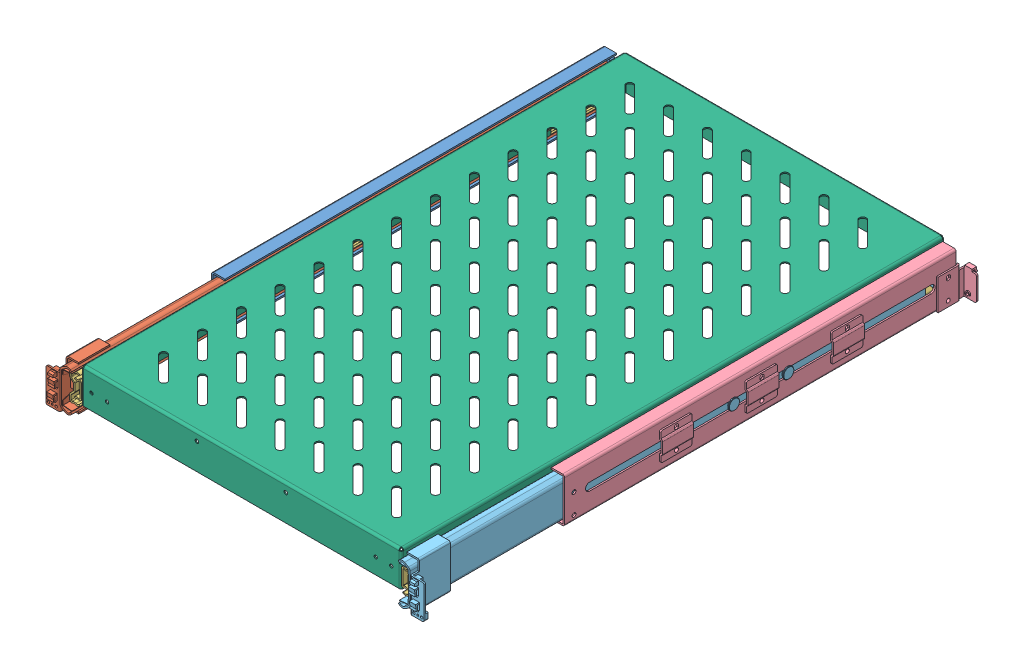
SolidWorks assembly 5501_725, configuration Default. Lengths in mm.
Overall size (486.62 58.55 723.92).
7 component instances, 6 part files, 22 mates.
Components (placement in the parent):
- 5501_725-holder-left-1: 5501_725-holder-left [Default] at (36.97 -28.7 -701.36) x (0 0 1) z (1 0 0) size (521.69 57.4 33.33)
- 5501_725-holder-inner-left-1: 5501_725-holder-inner-left [Default] at (36.97 -28.7 -690) x (0 0 1) z (1 0 0) size (695.13 57.4 33.04)
- 5501_725-rail-1: 5501_725-rail [Default] at (37.31 -28.7 -698.1158) x (0 0 1) z (1 0 0) size (690 37.86 21.27)
- 5501_725-holder-right-1: 5501_725-holder-right [Default] at (449.65 -28.7 -701.36) x (0 0 1) z (-1 0 0) size (521.69 57.4 33.33)
- 5501_725-holder-inner-right-1: 5501_725-holder-inner-right [Default] at (449.65 -28.7 -690) x (0 0 1) z (-1 0 0) size (695.13 57.4 33.04)
- 5501_725-rail-2: 5501_725-rail [Default] at (449.31 -28.7 -698.1158) x (0 0 1) z (-1 0 0) size (690 37.86 21.27)
- 5501_725-plate-1: 5501_725-plate [Default] at (243.31 -43.85 -8.1658) size (412 45 700)
Mates (geometry in assembly coordinates):
- Deckungsgleich1: coincident aligned: plane of 5501_725-holder-inner-left-1 through (27.78 -49.645 0) normal (0 0 1); plane of assembly through (0 0 0) normal (0 0 1)
- Deckungsgleich2: coincident aligned: plane of 5501_725-holder-inner-left-1 through (32.111 0 -10) normal (0 1 0); plane of assembly through (0 0 0) normal (0 1 0)
- Deckungsgleich3: coincident anti-aligned: plane of 5501_725-holder-inner-left-1 through (0 -57.4 0) normal (-1 0 0); plane of assembly through (0 0 0) normal (1 0 0)
- Breite1: width: plane of 5501_725-holder-left-1 through (18 -23.7 -669.096) normal (0 -1 0); plane of 5501_725-holder-left-1 through (18 -33.7 -229.096) normal (0 1 0); cylinder of 5501_725-holder-inner-left-1 through (18.131 -28.7 -414) axis (1 0 0) radius 4.95
- Breite2: width: plane of 5501_725-holder-left-1 through (18 -23.7 -669.096) normal (0 -1 0); plane of 5501_725-holder-left-1 through (18 -33.7 -229.096) normal (0 1 0); cylinder of 5501_725-holder-inner-left-1 through (18.131 -28.7 -484) axis (1 0 0) radius 4.95
- Deckungsgleich4: coincident anti-aligned: plane of 5501_725-holder-left-1 through (18 -55.4 -197.1) normal (1 0 0); plane of 5501_725-holder-inner-left-1 through (18 -6.946 0) normal (-1 0 0)
- Abstand1: distance = 713.3 mm anti-aligned: plane of 5501_725-holder-left-1 through (0.028 -57.4 -713.3) normal (0 0 -1); plane of 5501_725-holder-inner-left-1 through (27.78 -49.645 0) normal (0 0 1)
- Breite3: width anti-aligned: plane of 5501_725-rail-1 through (29.43 -33.41 -13.7358) normal (0 -1 0); plane of 5501_725-rail-1 through (29.43 -23.99 -13.7358) normal (0 1 0); plane of 5501_725-holder-inner-left-1 through (36.97 -22.7 -690) normal (0 1 0); plane of 5501_725-holder-inner-left-1 through (36.97 -34.7 -690) normal (0 -1 0)
- Abstand2: distance = 1 mm anti-aligned: plane of 5501_725-holder-inner-left-1 through (21.33 -48.252 -0.84) normal (1 0 0); plane of 5501_725-rail-1 through (22.33 -38.901 -8.1158) normal (-1 0 0)
- LimitAbstand1: limit distance = 0 mm: cylinder of 5501_725-rail-1 through (20.5 -28.7 -689.8468) axis (1 0 0) radius 3.1; plane of 5501_725-holder-inner-left-1 through (32.16 -33.8 -677.4) normal (0 0 1)
- Deckungsgleich9: coincident anti-aligned: plane of 5501_725-rail-1 through (37.31 -40.356 -8.1158) normal (1 0 0); plane of 5501_725-plate-1 through (37.31 -0.35 -708.1658) normal (-1 0 0)
- Breite4: width aligned: plane of 5501_725-rail-1 through (39.06 -32.95 -351.8158) normal (0 0 1); plane of 5501_725-rail-1 through (39.06 -32.95 -364.5158) normal (0 0 -1); plane of 5501_725-plate-1 through (38.81 -38.85 -368.1658) normal (0 0 1); plane of 5501_725-plate-1 through (38.81 -33.85 -348.1658) normal (0 0 -1)
- Deckungsgleich10: coincident anti-aligned: plane of 5501_725-rail-1 through (37.56 -22.35 -610.2458) normal (0 1 0); plane of 5501_725-plate-1 through (38.81 -22.35 -621.1658) normal (0 -1 0)
- Deckungsgleich11: coincident anti-aligned: plane of 5501_725-rail-2 through (449.31 -17.044 -8.1158) normal (-1 0 0); plane of 5501_725-plate-1 through (449.31 -0.35 -8.1658) normal (1 0 0)
- Deckungsgleich12: coincident aligned: plane of 5501_725-rail-1 through (37.31 -28.7 -8.1158) normal (0 0 1); plane of 5501_725-rail-2 through (449.31 -28.7 -8.1158) normal (0 0 1)
- Deckungsgleich13: coincident aligned: plane of 5501_725-rail-1 through (29.43 -23.99 -13.7358) normal (0 1 0); plane of 5501_725-rail-2 through (457.19 -23.99 -13.7358) normal (0 1 0)
- Deckungsgleich15: coincident aligned: plane of 5501_725-holder-inner-left-1 through (32.111 0 -10) normal (0 1 0); plane of 5501_725-holder-inner-right-1 through (470.62 0 -10) normal (0 1 0)
- Deckungsgleich16: coincident aligned: plane of 5501_725-holder-inner-left-1 through (27.78 -49.645 0) normal (0 0 1); plane of 5501_725-holder-inner-right-1 through (458.84 -7.755 0) normal (0 0 1)
- Abstand4: distance = 1 mm anti-aligned: plane of 5501_725-rail-2 through (464.29 -18.499 -8.1158) normal (1 0 0); plane of 5501_725-holder-inner-right-1 through (465.29 -9.148 -0.84) normal (-1 0 0)
- Deckungsgleich18: coincident aligned: plane of 5501_725-holder-left-1 through (33.361 0 -197.1) normal (0 1 0); plane of 5501_725-holder-right-1 through (470.62 0 -197.1) normal (0 1 0)
- Deckungsgleich19: coincident anti-aligned: plane of 5501_725-holder-right-1 through (468.62 -2 -197.1) normal (-1 0 0); plane of 5501_725-holder-inner-right-1 through (468.62 -50.454 0) normal (1 0 0)
- Deckungsgleich20: coincident aligned: plane of 5501_725-holder-left-1 through (0.028 -57.4 -713.3) normal (0 0 -1); plane of 5501_725-holder-right-1 through (486.592 -17.7 -713.3) normal (0 0 -1)
